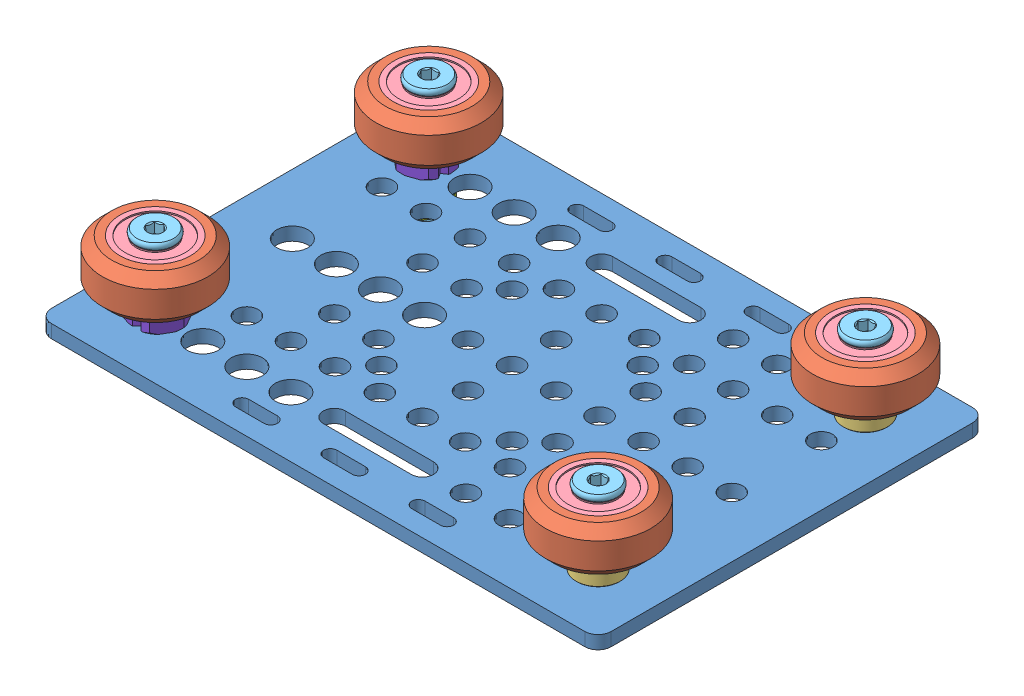
SolidWorks assembly Dispenser Carriage, configuration Default. Lengths in mm.
Overall size (129.92 31.62 91.41).
29 component instances, 8 part files, 56 mates.
Components (placement in the parent):
- V-Slot Gantry Plate 20-80mm-1: V-Slot Gantry Plate 20-80mm [Default] at (34.0048 63.5 105.4214) size (127 3 88)
- Solid V Wheel-1: Solid V Wheel [Default] at (83.8548 77.6 75.1014) x (0 -1 0) z (0.999476 0 0.032382) size (10.2 23.9 23.9)
- Aluminum Spacer 6mm-1: Aluminum Spacer 6mm [Default] at (83.8548 72.5 75.1014) x (0 0 -1) z (0 -1 0) size (10 10 6)
- Ball Bearing 5 x 16 x 5-2: Ball Bearing 5 x 16 x 5 [Default] at (83.8548 75 75.1014) x (0 -1 0) z (0.999476 0 0.032382) size (5 16 16)
- Ball Bearing 5 x 16 x 5-3: Ball Bearing 5 x 16 x 5 [Default] at (83.8548 80.2 75.1014) x (0 -1 0) z (0 0 1) size (5 16 16)
- Low Profile Screw M5-6: Low Profile Screw M5 [M5 x 30] at (83.8548 52.7 75.1014) x (0 -1 0) z (0 0 1) size (31.62 9 9)
- STDWasher-1: STDWasher [Default] at (83.8548 62.5 75.1014) size (10 1 10)
- STDNut-1: STDNut [Default] at (83.8548 58.5 75.1014) size (9.24 4 8)
- Solid V Wheel-2: Solid V Wheel [Default] at (83.8548 77.6 135.7414) x (0 -1 0) z (0.8922 0 -0.451641) size (10.2 23.9 23.9)
- Ball Bearing 5 x 16 x 5-4: Ball Bearing 5 x 16 x 5 [Default] at (83.8548 75 135.7414) x (0 -1 0) z (0.31005 0 0.95072) size (5 16 16)
- Ball Bearing 5 x 16 x 5-5: Ball Bearing 5 x 16 x 5 [Default] at (83.8548 80.2 135.7414) x (0 -1 0) z (0 0 1) size (5 16 16)
- Low Profile Screw M5-7: Low Profile Screw M5 [M5 x 30] at (83.8548 52.7 135.7414) x (0 -1 0) z (0 0 1) size (31.62 9 9)
- STDNut-2: STDNut [Default] at (83.8548 62.5 135.7414) x (0.171747 0 0.985141) z (0.985141 0 -0.171747) size (9.24 4 8)
- STDWasher-2: STDWasher [Default] at (83.8548 63.5 135.7414) x (-0.642484 0 -0.766299) z (-0.766299 0 0.642484) size (10 1 10)
- Aluminum Spacer 6mm-2: Aluminum Spacer 6mm [Default] at (83.8548 72.5 135.7414) x (1 0 0) z (0 -1 0) size (10 10 6)
- Eccentric Spacer 6mm-1: Eccentric Spacer 6mm [Default] at (-15.8452 66.5 75.1014) x (0.185827 0 -0.982583) z (0.982583 0 0.185827) size (11.55 8.5 10)
- Solid V Wheel-3: Solid V Wheel [Default] at (-15.069 77.6 75.2482) x (0 -1 0) z (0.284229 0 0.958756) size (10.2 23.9 23.9)
- Ball Bearing 5 x 16 x 5-6: Ball Bearing 5 x 16 x 5 [Default] at (-15.069 80.2 75.2482) x (0 -1 0) z (0 0 1) size (5 16 16)
- Ball Bearing 5 x 16 x 5-7: Ball Bearing 5 x 16 x 5 [Default] at (-15.069 75 75.2482) x (0 -1 0) z (0 0 1) size (5 16 16)
- Low Profile Screw M5-8: Low Profile Screw M5 [M5 x 30] at (-15.069 52.7 75.2482) x (0 -1 0) z (0 0 1) size (31.62 9 9)
- STDNut-3: STDNut [Default] at (-15.069 58.5 75.2482) size (9.24 4 8)
- STDWasher-3: STDWasher [Default] at (-15.069 62.5 75.2482) size (10 1 10)
- Eccentric Spacer 6mm-2: Eccentric Spacer 6mm [Default] at (-15.8452 66.5 135.7414) size (11.55 8.5 10)
- Solid V Wheel-4: Solid V Wheel [Default] at (-15.8452 77.6 136.5314) x (0 -1 0) z (0.206271 0 -0.978495) size (10.2 23.9 23.9)
- Ball Bearing 5 x 16 x 5-8: Ball Bearing 5 x 16 x 5 [Default] at (-15.8452 75 136.5314) x (0 -1 0) z (0 0 1) size (5 16 16)
- Ball Bearing 5 x 16 x 5-9: Ball Bearing 5 x 16 x 5 [Default] at (-15.8452 80.2 136.5314) x (0 -1 0) z (0.107497 0 0.994205) size (5 16 16)
- Low Profile Screw M5-9: Low Profile Screw M5 [M5 x 30] at (-15.8452 52.7 136.5314) x (0 -1 0) z (0.34232 0 0.939583) size (31.62 9 9)
- STDNut-4: STDNut [Default] at (-15.8452 58.5 136.5314) x (0.939583 0 -0.34232) z (0.34232 0 0.939583) size (9.24 4 8)
- STDWasher-4: STDWasher [Default] at (-15.8452 62.5 136.5314) x (0.939583 0 -0.34232) z (0.34232 0 0.939583) size (10 1 10)
Mates (geometry in assembly coordinates):
- Concentric5: concentric aligned: cylinder of Solid V Wheel-1 through (83.8548 77.6 75.1014) axis (0 -1 0) radius 8; cylinder of Ball Bearing 5 x 16 x 5-2 through (83.8548 75 75.1014) axis (0 -1 0) radius 8
- Coincident2: coincident aligned: plane of Solid V Wheel-1 through (84.1139 72.5 67.1056) normal (0 -1 0); plane of Ball Bearing 5 x 16 x 5-2 through (84.075 72.5 68.305) normal (0 -1 0)
- Concentric6: concentric aligned: cylinder of Solid V Wheel-1 through (83.8548 77.6 75.1014) axis (0 -1 0) radius 8; cylinder of Ball Bearing 5 x 16 x 5-3 through (83.8548 80.2 75.1014) axis (0 -1 0) radius 8
- Coincident3: coincident aligned: plane of Solid V Wheel-1 through (84.1139 82.7 67.1056) normal (0 1 0); plane of Ball Bearing 5 x 16 x 5-3 through (90.6548 82.7 75.1014) normal (0 1 0)
- Coincident5: coincident anti-aligned: plane of Aluminum Spacer 6mm-1 through (83.8548 72.5 75.1014) normal (0 1 0); plane of Ball Bearing 5 x 16 x 5-2 through (83.9358 72.5 72.6027) normal (0 -1 0)
- Concentric9: concentric aligned: cylinder of Ball Bearing 5 x 16 x 5-3 through (83.8548 80.2 75.1014) axis (0 -1 0) radius 2.5; cylinder of Low Profile Screw M5-6 through (83.8548 82.7 75.1014) axis (0 -1 0) radius 2.5
- Coincident6: coincident anti-aligned: plane of Ball Bearing 5 x 16 x 5-3 through (86.3548 82.7 75.1014) normal (0 1 0); plane of Low Profile Screw M5-6 through (88.0162 82.7 75.1014) normal (0 -1 0)
- Concentric10: concentric anti-aligned: cylinder of Aluminum Spacer 6mm-1 through (83.8548 66.5 75.1014) axis (0 1 0) radius 2.55; cylinder of Low Profile Screw M5-6 through (83.8548 82.7 75.1014) axis (0 -1 0) radius 2.5
- Concentric11: concentric aligned: cylinder of V-Slot Gantry Plate 20-80mm-1 through (83.8548 66.5 75.1014) axis (0 -1 0) radius 2.55; cylinder of Low Profile Screw M5-6 through (83.8548 82.7 75.1014) axis (0 -1 0) radius 2.5
- Coincident8: coincident anti-aligned: plane of V-Slot Gantry Plate 20-80mm-1 through (-26.4952 66.5 146.4214) normal (0 1 0); plane of Aluminum Spacer 6mm-1 through (83.8548 66.5 75.1014) normal (0 -1 0)
- Concentric13: concentric aligned: cylinder of Low Profile Screw M5-6 through (83.8548 82.7 75.1014) axis (0 -1 0) radius 2.5; cylinder of STDWasher-1 through (83.8548 63.5 75.1014) axis (0 -1 0) radius 2.5
- Coincident10: coincident anti-aligned: plane of V-Slot Gantry Plate 20-80mm-1 through (-26.4952 63.5 146.4214) normal (0 -1 0); plane of STDWasher-1 through (83.8548 63.5 75.1014) normal (0 1 0)
- Concentric15: concentric aligned: cylinder of Low Profile Screw M5-6 through (83.8548 82.7 75.1014) axis (0 -1 0) radius 2.5; cylinder of STDNut-1 through (83.8548 62.5 75.1014) axis (0 -1 0) radius 2.5
- Coincident11: coincident anti-aligned: plane of STDWasher-1 through (83.8548 62.5 75.1014) normal (0 -1 0); plane of STDNut-1 through (83.8548 62.5 75.1014) normal (0 1 0)
- Concentric16: concentric aligned: cylinder of Solid V Wheel-2 through (83.8548 77.6 135.7414) axis (0 -1 0) radius 8; cylinder of Ball Bearing 5 x 16 x 5-4 through (83.8548 75 135.7414) axis (0 -1 0) radius 8
- Coincident12: coincident aligned: plane of Solid V Wheel-2 through (80.2417 72.5 128.6038) normal (0 -1 0); plane of Ball Bearing 5 x 16 x 5-4 through (90.3197 72.5 133.6331) normal (0 -1 0)
- Concentric17: concentric aligned: cylinder of Solid V Wheel-2 through (83.8548 77.6 135.7414) axis (0 -1 0) radius 8; cylinder of Ball Bearing 5 x 16 x 5-5 through (83.8548 80.2 135.7414) axis (0 -1 0) radius 8
- Coincident13: coincident aligned: plane of Solid V Wheel-2 through (80.2417 82.7 128.6038) normal (0 1 0); plane of Ball Bearing 5 x 16 x 5-5 through (90.6548 82.7 135.7414) normal (0 1 0)
- Concentric18: concentric aligned: cylinder of Ball Bearing 5 x 16 x 5-5 through (83.8548 80.2 135.7414) axis (0 -1 0) radius 2.5; cylinder of Low Profile Screw M5-7 through (83.8548 82.7 135.7414) axis (0 -1 0) radius 2.5
- Coincident14: coincident anti-aligned: plane of Ball Bearing 5 x 16 x 5-5 through (86.3548 82.7 135.7414) normal (0 1 0); plane of Low Profile Screw M5-7 through (88.0162 82.7 135.7414) normal (0 -1 0)
- Concentric19: concentric anti-aligned: cylinder of Low Profile Screw M5-7 through (83.8548 82.7 135.7414) axis (0 -1 0) radius 2.5; cylinder of STDWasher-2 through (83.8548 62.5 135.7414) axis (0 1 0) radius 2.5
- Concentric20: concentric anti-aligned: cylinder of Low Profile Screw M5-7 through (83.8548 82.7 135.7414) axis (0 -1 0) radius 2.5; cylinder of STDNut-2 through (83.8548 58.5 135.7414) axis (0 1 0) radius 2.5
- Coincident16: coincident anti-aligned: plane of STDNut-2 through (83.8548 62.5 135.7414) normal (0 1 0); plane of STDWasher-2 through (83.8548 62.5 135.7414) normal (0 -1 0)
- Concentric21: concentric aligned: cylinder of V-Slot Gantry Plate 20-80mm-1 through (83.8548 66.5 135.7414) axis (0 -1 0) radius 2.55; cylinder of Low Profile Screw M5-7 through (83.8548 82.7 135.7414) axis (0 -1 0) radius 2.5
- Concentric22: concentric anti-aligned: cylinder of Low Profile Screw M5-7 through (83.8548 82.7 135.7414) axis (0 -1 0) radius 2.5; cylinder of Aluminum Spacer 6mm-2 through (83.8548 66.5 135.7414) axis (0 1 0) radius 2.55
- Coincident18: coincident anti-aligned: plane of Ball Bearing 5 x 16 x 5-4 through (86.2316 72.5 134.9663) normal (0 -1 0); plane of Aluminum Spacer 6mm-2 through (83.8548 72.5 135.7414) normal (0 1 0)
- Coincident19: coincident anti-aligned: plane of V-Slot Gantry Plate 20-80mm-1 through (-26.4952 66.5 146.4214) normal (0 1 0); plane of Aluminum Spacer 6mm-2 through (83.8548 66.5 135.7414) normal (0 -1 0)
- Coincident20: coincident anti-aligned: plane of V-Slot Gantry Plate 20-80mm-1 through (-26.4952 63.5 146.4214) normal (0 -1 0); plane of STDWasher-2 through (83.8548 63.5 135.7414) normal (0 1 0)
- Concentric23: concentric aligned: cylinder of Solid V Wheel-3 through (-15.069 77.6 75.2482) axis (0 -1 0) radius 8; cylinder of Ball Bearing 5 x 16 x 5-7 through (-15.069 75 75.2482) axis (0 -1 0) radius 8
- Coincident21: coincident aligned: plane of Solid V Wheel-3 through (-7.3989 72.5 72.9744) normal (0 -1 0); plane of Ball Bearing 5 x 16 x 5-7 through (-8.269 72.5 75.2482) normal (0 -1 0)
- Concentric24: concentric aligned: cylinder of Solid V Wheel-3 through (-15.069 77.6 75.2482) axis (0 -1 0) radius 8; cylinder of Ball Bearing 5 x 16 x 5-6 through (-15.069 80.2 75.2482) axis (0 -1 0) radius 8
- Coincident22: coincident aligned: plane of Solid V Wheel-3 through (-7.3989 82.7 72.9744) normal (0 1 0); plane of Ball Bearing 5 x 16 x 5-6 through (-8.269 82.7 75.2482) normal (0 1 0)
- Concentric25: concentric aligned: cylinder of Ball Bearing 5 x 16 x 5-6 through (-15.069 80.2 75.2482) axis (0 -1 0) radius 2.5; cylinder of Low Profile Screw M5-8 through (-15.069 82.7 75.2482) axis (0 -1 0) radius 2.5
- Coincident23: coincident anti-aligned: plane of Ball Bearing 5 x 16 x 5-6 through (-12.569 82.7 75.2482) normal (0 1 0); plane of Low Profile Screw M5-8 through (-10.9075 82.7 75.2482) normal (0 -1 0)
- Coincident27: coincident anti-aligned: plane of Eccentric Spacer 6mm-1 through (-15.8452 72.5 75.1014) normal (0 1 0); plane of Ball Bearing 5 x 16 x 5-7 through (-12.569 72.5 75.2482) normal (0 -1 0)
- Concentric29: concentric anti-aligned: cylinder of Eccentric Spacer 6mm-1 through (-15.069 64 75.2482) axis (0 1 0) radius 2.5; cylinder of Low Profile Screw M5-8 through (-15.069 82.7 75.2482) axis (0 -1 0) radius 2.5
- Concentric30: concentric anti-aligned: cylinder of V-Slot Gantry Plate 20-80mm-1 through (-15.8452 66.5 75.1014) axis (0 -1 0) radius 3.55; cylinder of Eccentric Spacer 6mm-1 through (-15.8452 64 75.1014) axis (0 1 0) radius 3.555
- Coincident28: coincident anti-aligned: plane of V-Slot Gantry Plate 20-80mm-1 through (-26.4952 66.5 146.4214) normal (0 1 0); plane of Eccentric Spacer 6mm-1 through (-15.8452 66.5 75.1014) normal (0 -1 0)
- Coincident29: coincident anti-aligned: plane of V-Slot Gantry Plate 20-80mm-1 through (-26.4952 63.5 146.4214) normal (0 -1 0); plane of STDWasher-3 through (-15.069 63.5 75.2482) normal (0 1 0)
- Concentric31: concentric aligned: cylinder of Low Profile Screw M5-8 through (-15.069 82.7 75.2482) axis (0 -1 0) radius 2.5; cylinder of STDWasher-3 through (-15.069 63.5 75.2482) axis (0 -1 0) radius 2.5
- Concentric32: concentric aligned: cylinder of Low Profile Screw M5-8 through (-15.069 82.7 75.2482) axis (0 -1 0) radius 2.5; cylinder of STDNut-3 through (-15.069 62.5 75.2482) axis (0 -1 0) radius 2.5
- Coincident30: coincident anti-aligned: plane of STDNut-3 through (-15.069 62.5 75.2482) normal (0 1 0); plane of STDWasher-3 through (-15.069 62.5 75.2482) normal (0 -1 0)
- Concentric33: concentric aligned: cylinder of Solid V Wheel-4 through (-15.8452 77.6 136.5314) axis (0 -1 0) radius 8; cylinder of Ball Bearing 5 x 16 x 5-9 through (-15.8452 80.2 136.5314) axis (0 -1 0) radius 8
- Coincident31: coincident aligned: plane of Solid V Wheel-4 through (-23.6732 82.7 134.8813) normal (0 1 0); plane of Ball Bearing 5 x 16 x 5-9 through (-9.0846 82.7 135.8004) normal (0 1 0)
- Concentric34: concentric aligned: cylinder of Solid V Wheel-4 through (-15.8452 77.6 136.5314) axis (0 -1 0) radius 8; cylinder of Ball Bearing 5 x 16 x 5-8 through (-15.8452 75 136.5314) axis (0 -1 0) radius 8
- Coincident32: coincident aligned: plane of Solid V Wheel-4 through (-23.6732 72.5 134.8813) normal (0 -1 0); plane of Ball Bearing 5 x 16 x 5-8 through (-9.0452 72.5 136.5314) normal (0 -1 0)
- Concentric35: concentric aligned: cylinder of Ball Bearing 5 x 16 x 5-9 through (-15.8452 80.2 136.5314) axis (0 -1 0) radius 2.5; cylinder of Low Profile Screw M5-9 through (-15.8452 82.7 136.5314) axis (0 -1 0) radius 2.5
- Coincident33: coincident anti-aligned: plane of Ball Bearing 5 x 16 x 5-9 through (-13.3597 82.7 136.2627) normal (0 1 0); plane of Low Profile Screw M5-9 through (-11.9352 82.7 135.1069) normal (0 -1 0)
- Concentric36: concentric anti-aligned: cylinder of Eccentric Spacer 6mm-2 through (-15.8452 64 136.5314) axis (0 1 0) radius 2.5; cylinder of Low Profile Screw M5-9 through (-15.8452 82.7 136.5314) axis (0 -1 0) radius 2.5
- Coincident34: coincident anti-aligned: plane of Eccentric Spacer 6mm-2 through (-15.8452 72.5 135.7414) normal (0 1 0); plane of Ball Bearing 5 x 16 x 5-8 through (-13.3452 72.5 136.5314) normal (0 -1 0)
- Concentric37: concentric anti-aligned: cylinder of V-Slot Gantry Plate 20-80mm-1 through (-15.8452 66.5 135.7414) axis (0 -1 0) radius 3.55; cylinder of Eccentric Spacer 6mm-2 through (-15.8452 64 135.7414) axis (0 1 0) radius 3.555
- Coincident35: coincident anti-aligned: plane of V-Slot Gantry Plate 20-80mm-1 through (-26.4952 66.5 146.4214) normal (0 1 0); plane of Eccentric Spacer 6mm-2 through (-15.8452 66.5 135.7414) normal (0 -1 0)
- Coincident36: coincident anti-aligned: plane of V-Slot Gantry Plate 20-80mm-1 through (-26.4952 63.5 146.4214) normal (0 -1 0); plane of STDWasher-4 through (-15.8452 63.5 136.5314) normal (0 1 0)
- Concentric38: concentric aligned: cylinder of Low Profile Screw M5-9 through (-15.8452 82.7 136.5314) axis (0 -1 0) radius 2.5; cylinder of STDWasher-4 through (-15.8452 63.5 136.5314) axis (0 -1 0) radius 2.5
- Concentric39: concentric aligned: cylinder of Low Profile Screw M5-9 through (-15.8452 82.7 136.5314) axis (0 -1 0) radius 2.5; cylinder of STDNut-4 through (-15.8452 62.5 136.5314) axis (0 -1 0) radius 2.5
- Coincident37: coincident anti-aligned: plane of STDNut-4 through (-15.8452 62.5 136.5314) normal (0 1 0); plane of STDWasher-4 through (-15.8452 62.5 136.5314) normal (0 -1 0)
